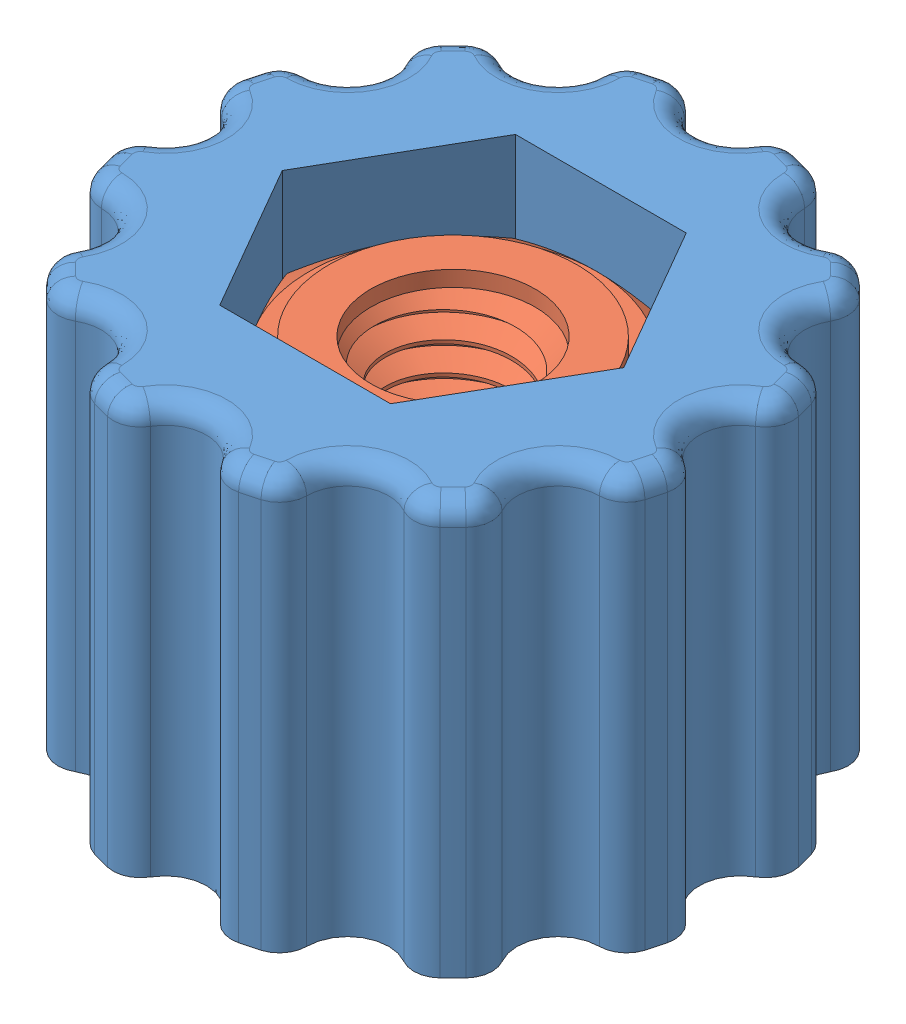
SolidWorks assembly M4_knob_assembly, configuration Default. Lengths in mm.
Overall size (13.67 10 13.67).
2 component instances, 2 part files, 3 mates.
Components (placement in the parent):
- Knob^M4_knob_assembly-1: Knob^M4_knob_assembly [Default] at origin size (13.67 10 13.67) (virtual)
- M4 x 0.7 Hex Nut-1: M4 x 0.7 Hex Nut [90592A090] at (0 6.6 0) x (0 0 1) z (-1 0 0) size (7 3.86 8.08)
Mates (geometry in assembly coordinates):
- Parallel1: parallel anti-aligned: plane of Knob^M4_knob_assembly-1 through (4.1569 5 0) normal (-0.866025 0 0.5); plane of M4 x 0.7 Hex Nut-1 through (4.0415 8.2 0) normal (0.866025 0 -0.5)
- Concentric1: concentric anti-aligned: circle of Knob^M4_knob_assembly-1; circle of M4 x 0.7 Hex Nut-1
- Coincident2: coincident anti-aligned: plane of Knob^M4_knob_assembly-1 through (0 5 0) normal (0 1 0); plane of M4 x 0.7 Hex Nut-1 through (2.0207 5 -3.5) normal (0 -1 0)
